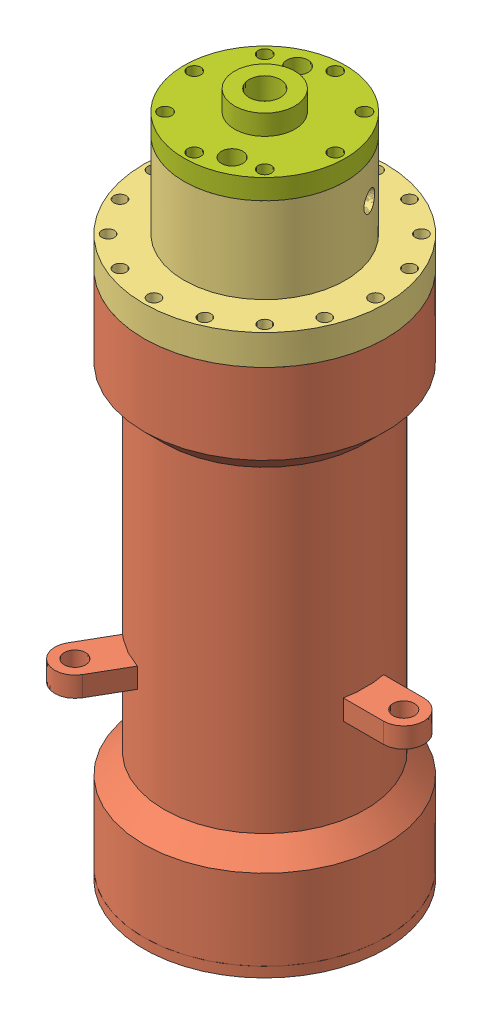
SolidWorks assembly cooling channel engine 4, configuration Default. Lengths in mm.
Overall size (176.52 431.77 177.16).
7 component instances, 7 part files, 16 mates.
Components (placement in the parent):
- pintle anulus plate_4-1: pintle anulus plate_4 [Default] at (0 -6.35 0) size (98.42 25.4 98.42)
- slot cooling jacket 6.1-1: slot cooling jacket 6.1 [Default] at origin size (176.52 333.35 177.16)
- dome_4-1: dome_4 [Default] at (0 6.35 0) size (152.4 73.03 152.4)
- pintle4-1: pintle4 [Default] at (0 79.375 0) x (0.94067 0 0.339322) z (-0.339322 0 0.94067) size (25.4 101.6 25.4)
- pintle sleve4-1: pintle sleve4 [Default] at (0 49.0371 0) size (38.1 64.29 38.1)
- pintle holder insert 4-1: pintle holder insert 4 [Default] at (0 66.675 0) x (0.998275 0 0.058716) z (-0.058716 0 0.998275) size (50.8 12.7 50.8)
- pintle lox connector4-1: pintle lox connector4 [Default] at (0 79.375 0) size (101.6 25.4 101.6)
Mates (geometry in assembly coordinates):
- Coincident4: coincident aligned: plane of pintle anulus plate_4-1 through (0 -6.35 0) normal (0 0 1)
- Coincident5: coordinate: point of slot cooling jacket 6.1-1
- Coincident6: coincident anti-aligned: plane of pintle anulus plate_4-1 through (-46.0375 0 0) normal (0 -1 0); plane of slot cooling jacket 6.1-1 through (-50.8 0 0) normal (0 1 0)
- Concentric4: concentric aligned: cylinder of pintle anulus plate_4-1 through (0 -48.65 0) axis (0 -1 0) radius 49.2125; cylinder of slot cooling jacket 6.1-1 through (0 -277.9245 0) axis (0 -1 0) radius 63.5
- Coincident7: coincident anti-aligned: plane of slot cooling jacket 6.1-1 through (-76.2 6.35 0) normal (0 1 0); plane of dome_4-1 through (-76.2 6.35 0) normal (0 -1 0)
- Concentric5: concentric aligned: cylinder of slot cooling jacket 6.1-1 through (0 -277.9245 0) axis (0 -1 0) radius 76.2; cylinder of dome_4-1 through (0 6.35 0) axis (0 -1 0) radius 76.2
- Concentric6: concentric aligned: cylinder of slot cooling jacket 6.1-1 through (-69.85 6.35 0) axis (0 1 0) radius 3.4544; cylinder of dome_4-1 through (-69.85 25.4 0) axis (0 1 0) radius 3.9688
- Concentric7: concentric anti-aligned: cylinder of slot cooling jacket 6.1-1 through (0 0 0) axis (0 -1 0) radius 46.0375; cylinder of pintle4-1 through (0 79.375 0) axis (0 1 0) radius 6.35
- Concentric8: concentric aligned: cylinder of pintle4-1 through (0 79.375 0) axis (0 1 0) radius 6.35; cylinder of pintle sleve4-1 through (0 49.0371 0) axis (0 1 0) radius 6.35
- Coincident8: coincident aligned: plane of pintle sleve4-1 through (0 49.0371 0) normal (0 0 1)
- Concentric9: concentric aligned: cylinder of slot cooling jacket 6.1-1 through (0 0 0) axis (0 -1 0) radius 46.0375; cylinder of pintle holder insert 4-1 through (0 66.675 0) axis (0 -1 0) radius 25.4
- Coincident9: coincident anti-aligned: plane of pintle4-1 through (-5.9733 73.025 -2.1547) normal (0 -1 0); plane of pintle holder insert 4-1 through (-11.4737 73.025 -0.6749) normal (0 1 0)
- Coincident10: coincident anti-aligned: plane of dome_4-1 through (-19.05 66.675 0) normal (0 1 0); plane of pintle holder insert 4-1 through (-20.2216 66.675 -1.1894) normal (0 -1 0)
- Concentric10: concentric anti-aligned: cylinder of dome_4-1 through (0 6.35 0) axis (0 -1 0) radius 50.8; cylinder of pintle lox connector4-1 through (0 104.775 0) axis (0 1 0) radius 50.8
- Coincident11: coincident anti-aligned: plane of dome_4-1 through (-25.4 79.375 0) normal (0 1 0); plane of pintle lox connector4-1 through (-19.431 79.375 0) normal (0 -1 0)
- Concentric11: concentric aligned: cylinder of dome_4-1 through (44.45 79.375 0) axis (0 1 0) radius 3.9688; cylinder of pintle lox connector4-1 through (44.45 92.075 0) axis (0 1 0) radius 4.2164
